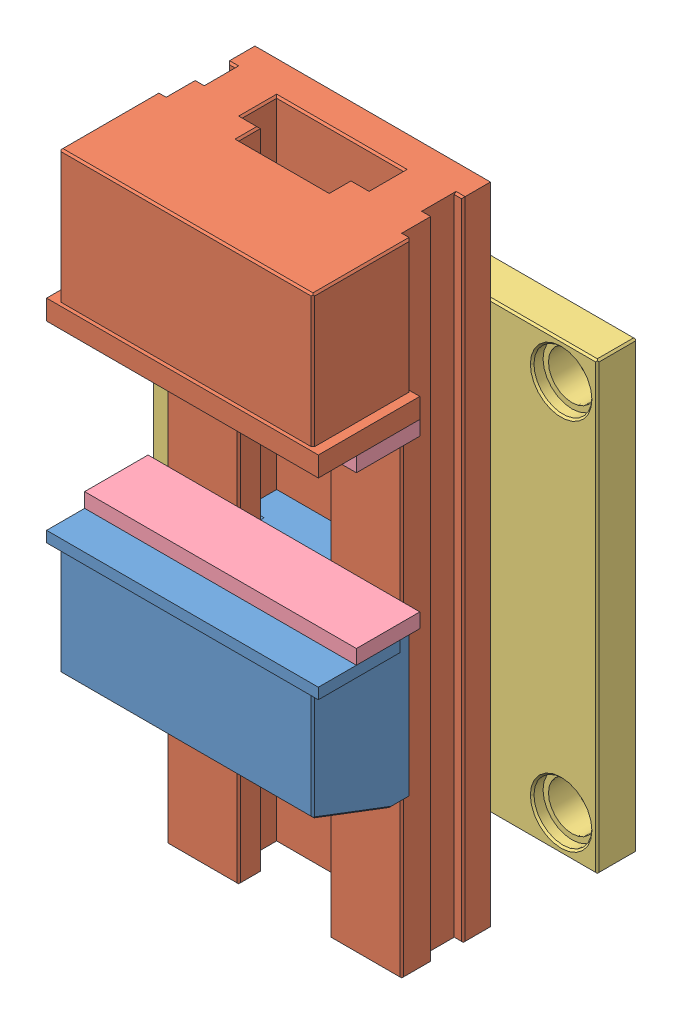
SolidWorks assembly ETAU SAGOP SUR PALETTE, configuration Défaut. Lengths in mm.
Overall size (246 357 128).
5 component instances, 4 part files, 12 mates.
Components (placement in the parent):
- Copie de Etau2^Etau c800-1: Copie de Etau2^Etau c800 [Défaut] at (-65 170 19) x (-1 0 0) z (0 0 1) size (150 83 87) (virtual)
- Copie de Etau1^Etau c800-1: Copie de Etau1^Etau c800 [Défaut] at origin size (150 357 106) (virtual)
- Copie de Plaque _X2_00E9_X0_tau^Etau c800-1: Copie de Plaque _X2_00E9_X0_tau^Etau c800 [Défaut] at (-65 177 -22) size (246 246 22) (virtual)
- Copie de CALE^Etau c800-1: Copie de CALE^Etau c800 [Défaut] at (10 177 67.5) x (0 -1 0) z (-1 0 0) size (8 35 150) (virtual)
- Copie de CALE^Etau c800-2: Copie de CALE^Etau c800 [Défaut] at (10 269 67.5) x (0 -1 0) z (-1 0 0) size (8 35 150) (virtual)
Mates (geometry in assembly coordinates):
- Coïncidente1: coincident anti-aligned: plane of Copie de Etau1^Etau c800-1 through (0 0 0) normal (0 0 -1); plane of Copie de Plaque _X2_00E9_X0_tau^Etau c800-1 through (-65 177 0) normal (0 0 1)
- Coaxiale1: concentric aligned: cylinder of Copie de Etau1^Etau c800-1 through (-65 237 10) axis (0 0 1) radius 13; cylinder of Copie de Plaque _X2_00E9_X0_tau^Etau c800-1 through (-65 237 -11.66) axis (0 0 1) radius 7
- Parallèle1: parallel aligned: plane of Copie de Etau1^Etau c800-1 through (-130 0 50) normal (-1 0 0); plane of Copie de Plaque _X2_00E9_X0_tau^Etau c800-1 through (-188 54 -22) normal (-1 0 0)
- Distance1: distance = 100 mm anti-aligned: plane of Copie de Etau1^Etau c800-1 through (0 273 0) normal (0 -1 0); plane of Copie de Etau2^Etau c800-1 through (-65 173 19) normal (0 1 0)
- Coïncidente4: coincident anti-aligned: plane of Copie de Etau2^Etau c800-1 through (-40 170 50) normal (0 0 -1); plane of Copie de Etau1^Etau c800-1 through (-130 0 50) normal (0 0 1)
- Coïncidente5: coincident anti-aligned: plane of Copie de Etau2^Etau c800-1 through (-90 170 50) normal (-1 0 0); plane of Copie de Etau1^Etau c800-1 through (-90 0 50) normal (1 0 0)
- Coïncidente6: coincident aligned: plane of Copie de CALE^Etau c800-1 through (-65 177 67.5) normal (-1 0 0); plane of Copie de CALE^Etau c800-2 through (-65 269 67.5) normal (-1 0 0)
- Coïncidente7: coincident aligned: plane of Copie de CALE^Etau c800-1 through (-140 173 50) normal (0 0 -1); plane of Copie de CALE^Etau c800-2 through (-140 265 50) normal (0 0 -1)
- Coïncidente9: coincident anti-aligned: plane of Copie de Etau1^Etau c800-1 through (-130 0 50) normal (0 0 1); plane of Copie de CALE^Etau c800-2 through (-140 265 50) normal (0 0 -1)
- Coïncidente10: coincident anti-aligned: plane of Copie de Etau1^Etau c800-1 through (0 273 0) normal (0 -1 0); plane of Copie de CALE^Etau c800-2 through (-140 273 50) normal (0 1 0)
- Coïncidente11: coincident anti-aligned: plane of Copie de Etau2^Etau c800-1 through (-65 173 19) normal (0 1 0); plane of Copie de CALE^Etau c800-1 through (-140 173 50) normal (0 -1 0)
- Coïncidente12: coincident aligned: plane of Copie de CALE^Etau c800-2 through (-65 269 67.5) normal (-1 0 0); plane of assembly through (-65 0 0) normal (-1 0 0)
